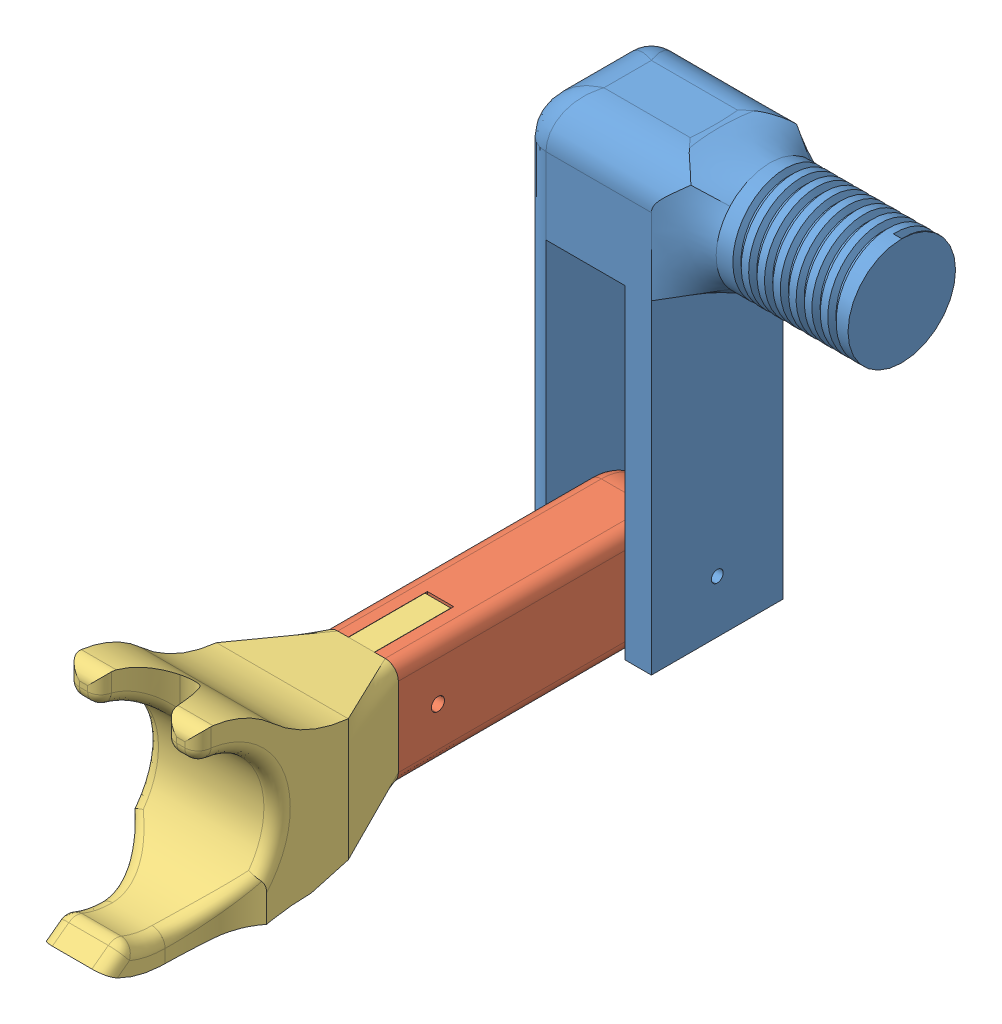
SolidWorks assembly Montagem_braco, configuration Valor predeterminado. Lengths in mm.
Overall size (121.5 183.78 245.15).
3 component instances, 3 part files, 6 mates.
Components (placement in the parent):
- Braço-2: Braço [Valor predeterminado] at (37.4923 -77.9656 133.357) x (0 1 0) z (0 0 1) size (168.75 120 50.02)
- antebraço 2-1: antebraço 2 [Valor predeterminado] at (26.4923 -77.9656 148.357) x (0 0 1) z (-1 0 0) size (120 40 28)
- mão versao 2-1: mão versao 2 [Valor predeterminado] at (37.4923 -70.0385 258.357) x (-1 0 0) z (0 0 -1) size (52.99 82 139.15)
Mates (geometry in assembly coordinates):
- Concêntrico1: concentric: cylinder of Braço-2 through (37.4923 -57.9656 158.357) axis (-1 0 0) radius 2.25; cylinder of antebraço 2-1 through (-1.5077 -57.9656 158.357) axis (1 0 0) radius 2.25
- Distância1: distance = 1 mm: plane of antebraço 2-1 through (-1.5077 -77.9656 148.357) normal (-1 0 0); plane of Braço-2 through (-2.5077 45.0344 183.357) normal (1 0 0)
- Paralelo1: parallel anti-aligned: plane of antebraço 2-1 through (-1.5077 -77.9656 148.357) normal (0 -1 0)
- Concêntrico2: concentric: cylinder of antebraço 2-1 through (38.4923 -57.9656 253.357) axis (-1 0 0) radius 2.5; cylinder of mão versao 2-1 through (-12.6077 -57.9656 253.357) axis (1 0 0) radius 2.5
- Coincidente8: coincident anti-aligned: plane of antebraço 2-1 through (-1.5077 -77.9656 268.357) normal (0 0 1); plane of mão versao 2-1 through (3.4923 -72.9656 268.357) normal (0 0 -1)
- Coincidente9: coincident: point of assembly; point of assembly; moEndPointRef_w of antebraço 2-1; moEndPointRef_w of mão versao 2-1
